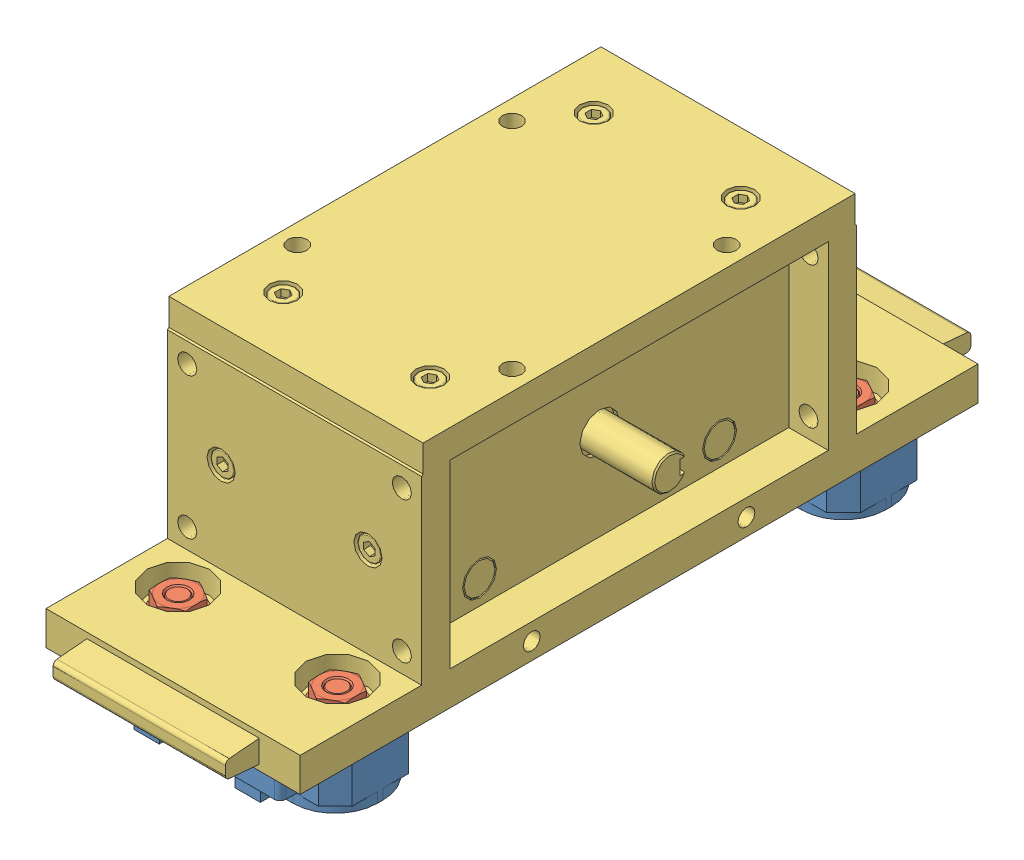
SolidWorks assembly without alum, configuration Default. Lengths in mm.
Overall size (112.01 104 264).
9 component instances, 3 part files, 0 mates.
Components (placement in the parent):
- DLS3C_CS-1: DLS3C_CS [Default] at (-28.2 74.3 -809.8) x (0 0 1) z (1 0 0) size (55 20.9 30)
- DLS3C_SJ25C-1: DLS3C_SJ25C [Default] at (-28.2 74.3 -809.8) x (1 0 0) z (0 0 -1) size (25 26.61 25)
- DLS3C_CS-2: DLS3C_CS [Default] at (-28.2 74.3 -989.8) x (0 0 1) z (1 0 0) size (55 20.9 30)
- DLS3C_SJ25C-2: DLS3C_SJ25C [Default] at (-28.2 74.3 -989.8) x (1 0 0) z (0 0 -1) size (25 26.61 25)
- DLS3C_CS-3: DLS3C_CS [Default] at (28.2 74.3 -809.8) x (0 0 -1) z (-1 0 0) size (55 20.9 30)
- DLS3C_SJ25C-3: DLS3C_SJ25C [Default] at (28.2 74.3 -809.8) x (1 0 0) z (0 0 -1) size (25 26.61 25)
- DLS3C_CS-4: DLS3C_CS [Default] at (28.2 74.3 -989.8) x (0 0 -1) z (-1 0 0) size (55 20.9 30)
- DLS3C_SJ25C-4: DLS3C_SJ25C [Default] at (28.2 74.3 -989.8) x (1 0 0) z (0 0 -1) size (25 26.61 25)
- DLS3CKKR_C-1: DLS3CKKR_C [Default] at (0 74.3 -899.8) size (112.01 86 264)
